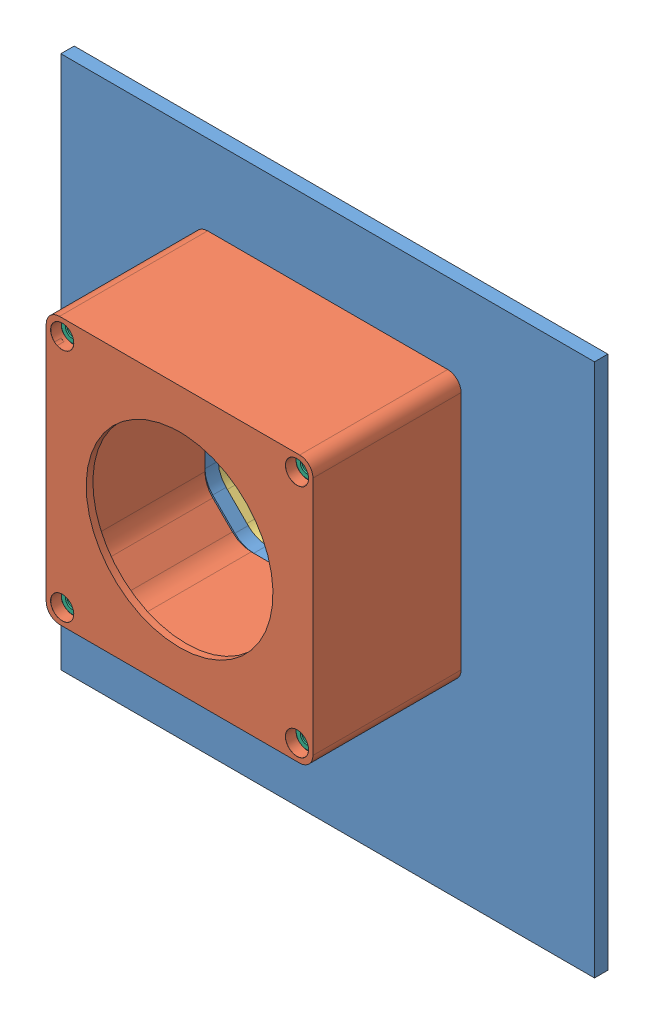
SolidWorks assembly Window Assembly, configuration Default. Lengths in mm.
Overall size (254 254 91.12).
15 component instances, 6 part files, 29 mates.
Components (placement in the parent):
- Door-1: Door [Default] at (-28.7272 28.7233 174.2223) size (254 254 6.35)
- conductive bushing-1: conductive bushing [Default] at (98.2728 181.1233 251.0573) x (1 0 0) z (0 1 0) size (127 70.48 127)
- conductive bushing outside-1: conductive bushing outside [Default] at (98.2728 181.1233 188.5098) x (1 0 0) z (0 1 0) size (127 14.29 127)
- socket head cap screw_am-8: socket head cap screw_am [B18.3.1M - 6 x 1.0 x 50 Hex SHCS -- 50SHX] at (154.1528 237.0033 162.4748) x (0 0 1) z (-1 0 0) size (56 10 10)
- socket head cap screw_am-9: socket head cap screw_am [B18.3.1M - 6 x 1.0 x 50 Hex SHCS -- 50SHX] at (42.3928 237.0033 162.4748) x (0 0 1) z (-1 0 0) size (56 10 10)
- socket head cap screw_am-10: socket head cap screw_am [B18.3.1M - 6 x 1.0 x 50 Hex SHCS -- 50SHX] at (42.3928 125.2433 162.4748) x (0 0 1) z (-1 0 0) size (56 10 10)
- socket head cap screw_am-11: socket head cap screw_am [B18.3.1M - 6 x 1.0 x 50 Hex SHCS -- 50SHX] at (154.1528 125.2433 162.4748) x (0 0 1) z (-1 0 0) size (56 10 10)
- bolt cover-1: bolt cover [Default] at (154.1528 237.0033 159.9348) size (10.92 10.92 5.08)
- bolt cover-2: bolt cover [Default] at (42.3928 237.0033 159.9348) size (10.92 10.92 5.08)
- bolt cover-3: bolt cover [Default] at (42.3928 125.2433 159.9348) size (10.92 10.92 5.08)
- bolt cover-4: bolt cover [Default] at (154.1528 125.2433 159.9348) size (10.92 10.92 5.08)
- hex nut style 1_am-7: hex nut style 1_am [B18.2.4.1M - Hex nut, Style 1,  M6 x 1 --D-N] at (42.3928 237.0033 246.4473) size (10 11.55 5.2)
- hex nut style 1_am-8: hex nut style 1_am [B18.2.4.1M - Hex nut, Style 1,  M6 x 1 --D-N] at (154.1528 237.0033 246.4473) size (10 11.55 5.2)
- hex nut style 1_am-9: hex nut style 1_am [B18.2.4.1M - Hex nut, Style 1,  M6 x 1 --D-N] at (154.1528 125.2433 246.4473) size (10 11.55 5.2)
- hex nut style 1_am-10: hex nut style 1_am [B18.2.4.1M - Hex nut, Style 1,  M6 x 1 --D-N] at (42.3928 125.2433 246.4473) size (10 11.55 5.2)
Mates (geometry in assembly coordinates):
- Coincident1: coincident anti-aligned: plane of Door-1 through (-28.7272 28.7233 180.5723) normal (0 0 1); plane of conductive bushing-1 through (41.1228 238.2733 180.5723) normal (0 0 -1)
- Coincident3: coincident aligned: plane of Door-1 through (156.6928 216.3223 174.2223) normal (-1 0 0); plane of conductive bushing-1 through (156.6928 217.502 180.5723) normal (-1 0 0)
- Coincident8: coincident aligned: plane of Door-1 through (63.0738 239.5433 174.2223) normal (0 -1 0); plane of conductive bushing-1 through (61.8941 239.5433 180.5723) normal (0 -1 0)
- Coincident21: coincident anti-aligned: plane of Door-1 through (-28.7272 28.7233 174.2223) normal (0 0 -1); plane of conductive bushing outside-1 through (98.2728 181.1233 174.2223) normal (0 0 1)
- Coincident22: coincident: cylinder of conductive bushing-1 through (154.1528 125.2433 247.2473) axis (0 0 1) radius 3.5; circle of conductive bushing outside-1
- Concentric15: concentric anti-aligned: cylinder of conductive bushing outside-1 through (154.1528 237.0033 188.5098) axis (0 0 1) radius 3.5; cylinder of socket head cap screw_am-8 through (154.1528 237.0033 130.7248) axis (0 0 -1) radius 5
- Coincident24: coincident anti-aligned: plane of conductive bushing outside-1 through (157.6528 237.0033 168.4748) normal (0 0 -1); plane of socket head cap screw_am-8 through (154.1528 242.0033 168.4748) normal (0 0 1)
- Concentric161: concentric anti-aligned: cylinder of conductive bushing outside-1 through (42.3928 237.0033 188.5098) axis (0 0 1) radius 3.5; cylinder of socket head cap screw_am-9 through (42.3928 237.0033 130.7248) axis (0 0 -1) radius 5
- Coincident251: coincident anti-aligned: plane of conductive bushing outside-1 through (45.8928 237.0033 168.4748) normal (0 0 -1); plane of socket head cap screw_am-9 through (42.3928 242.0033 168.4748) normal (0 0 1)
- Concentric17: concentric anti-aligned: cylinder of conductive bushing outside-1 through (42.3928 125.2433 188.5098) axis (0 0 1) radius 3.5; cylinder of socket head cap screw_am-10 through (42.3928 125.2433 130.7248) axis (0 0 -1) radius 5
- Coincident26: coincident anti-aligned: plane of conductive bushing outside-1 through (45.8928 125.2433 168.4748) normal (0 0 -1); plane of socket head cap screw_am-10 through (42.3928 130.2433 168.4748) normal (0 0 1)
- Concentric18: concentric anti-aligned: cylinder of conductive bushing outside-1 through (154.1528 125.2433 188.5098) axis (0 0 1) radius 3.5; cylinder of socket head cap screw_am-11 through (154.1528 125.2433 130.7248) axis (0 0 -1) radius 5
- Coincident27: coincident anti-aligned: plane of conductive bushing outside-1 through (157.6528 125.2433 168.4748) normal (0 0 -1); plane of socket head cap screw_am-11 through (154.1528 130.2433 168.4748) normal (0 0 1)
- Concentric19: concentric aligned: circle of conductive bushing outside-1; cylinder of bolt cover-2 through (42.3928 237.0033 162.4748) axis (0 0 -1) radius 5.461
- Coincident29: coincident aligned: plane of conductive bushing outside-1 through (41.1228 238.2733 159.9348) normal (0 0 -1); plane of bolt cover-2 through (42.3928 237.0033 159.9348) normal (0 0 -1)
- Concentric20: concentric aligned: circle of conductive bushing outside-1; cylinder of bolt cover-1 through (154.1528 237.0033 162.4748) axis (0 0 -1) radius 5.461
- Coincident31: coincident aligned: plane of conductive bushing outside-1 through (41.1228 238.2733 159.9348) normal (0 0 -1); plane of bolt cover-1 through (154.1528 237.0033 159.9348) normal (0 0 -1)
- Coincident32: coincident aligned: plane of conductive bushing outside-1 through (41.1228 238.2733 159.9348) normal (0 0 -1); plane of bolt cover-4 through (154.1528 125.2433 159.9348) normal (0 0 -1)
- Concentric21: concentric anti-aligned: circle of conductive bushing outside-1; circle of bolt cover-4
- Concentric22: concentric anti-aligned: circle of conductive bushing outside-1; circle of bolt cover-3
- Coincident33: coincident aligned: plane of conductive bushing outside-1 through (41.1228 238.2733 159.9348) normal (0 0 -1); plane of bolt cover-3 through (42.3928 125.2433 159.9348) normal (0 0 -1)
- Concentric24: concentric: cylinder of conductive bushing-1 through (42.3928 237.0033 247.2473) axis (0 0 1) radius 3.5; cylinder of hex nut style 1_am-7 through (42.3928 237.0033 221.4098) axis (0 0 1) radius 3
- Coincident35: coincident: plane of conductive bushing-1 through (45.8928 237.0033 241.2473) normal (0 0 1); plane of hex nut style 1_am-7 through (32.3928 237.0033 241.2473) normal (0 0 -1)
- Concentric25: concentric: cylinder of conductive bushing-1 through (154.1528 237.0033 247.2473) axis (0 0 1) radius 5.5; cylinder of hex nut style 1_am-8 through (154.1528 237.2858 197.1139) axis (0 0 1) radius 3
- Coincident36: coincident: plane of conductive bushing-1 through (157.6528 237.0033 241.2473) normal (0 0 1); plane of hex nut style 1_am-8 through (144.1528 237.2858 216.9514) normal (0 0 -1)
- Concentric26: concentric: cylinder of conductive bushing-1 through (154.1528 125.2433 247.2473) axis (0 0 1) radius 5.5; cylinder of hex nut style 1_am-9 through (154.1528 125.2433 197.1139) axis (0 0 1) radius 3
- Coincident37: coincident: plane of conductive bushing-1 through (157.6528 125.2433 241.2473) normal (0 0 1); plane of hex nut style 1_am-9 through (144.1528 125.2433 216.9514) normal (0 0 -1)
- Concentric27: concentric: cylinder of conductive bushing-1 through (42.3928 125.2433 247.2473) axis (0 0 1) radius 5.5; cylinder of hex nut style 1_am-10 through (42.3928 125.2433 221.4098) axis (0 0 1) radius 3
- Coincident38: coincident: plane of conductive bushing-1 through (45.8928 125.2433 241.2473) normal (0 0 1); plane of hex nut style 1_am-10 through (32.3928 125.2433 241.2473) normal (0 0 -1)
